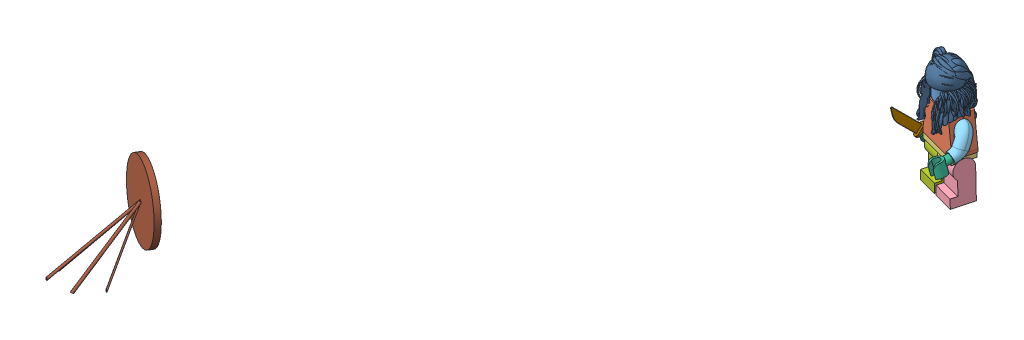
SolidWorks assembly Assemblage, configuration Default. Lengths in mm.
Overall size (131.52 71.94 248.3).
12 component instances, 11 part files, 29 mates.
Components (placement in the parent):
- hoofd-1: hoofd [Default] at (-2.0828 -36.2697 -1.4267) size (10 11.6 10)
- lichaam-1: lichaam [Default] at (-0.9943 -15.0822 -5.4791) x (0.96577 0 0.259401) z (0 -1 0) size (15.5 8 19)
- heup-1: heup [Default] at (-2.2734 -17.0822 -1.6809) x (0.96577 0 0.259401) z (-0.259401 0 0.96577) size (15 13 8)
- been-1: been [Default] at (-2.9578 -30.7822 2.7948) x (0.259401 0 -0.96577) z (0.96577 0 0.259401) size (8 14.7 7.5)
- arm-1: arm [Default] at (3.5968 -9.7563 4.5247) x (-0.026152 0.882476 -0.469631) z (0.303007 -0.440693 -0.844971) size (12.24 7.31 6.32)
- hand-1: hand [Default] at (5.5563 -16.2399 9.9413) x (0.245917 0.147876 -0.957944) z (0.931709 0.236466 0.275685) size (11.35 5.13 4.9)
- been 2-1: been 2 [Default] at (-3.9236 -30.7822 2.5354) x (0.259401 0 -0.96577) z (0.96577 0 0.259401) size (8 14.7 7.5)
- arm 2-1: arm 2 [Default] at (-9.3758 -11.9015 -2.7495) x (0.069651 0.936883 0.342635) z (0.296051 0.308582 -0.903953) size (12.24 7.31 6.32)
- hand-2: hand [Default] at (-11.3115 -19.7842 -4.6791) x (0.346001 0.785161 -0.513619) z (0.810219 0.025999 0.585551) size (11.35 5.13 4.9)
- zwaard-1: zwaard [Default] at (-11.2642 -19.8461 -4.7418) x (0.025074 0.721033 -0.692447) z (0.880649 0.311875 0.356639) size (4.65 17.55 3)
- haar goed 2-1: haar goed 2 [Default] at (-2.3434 5.7178 -0.4565) x (0.96577 0 0.259401) z (-0.259401 0 0.96577) size (16.74 21.71 15.98)
- bord-1: bord [Default] at (-98.3719 -6.3664 211.8563) x (0.483872 -0.373764 -0.791308) z (0.871266 0.120776 0.475719) size (24.24 40.74 26.3)
Mates (geometry in assembly coordinates):
- Concentric1: concentric aligned: cone of hoofd-1 through (-2.0828 -2.0822 -1.4267) axis (0 1 0); cone of lichaam-1 through (-2.0828 -2.0822 -1.4267) axis (0 1 0)
- Coincident2: coincident anti-aligned: plane of hoofd-1 through (1.4172 -2.0822 -1.4267) normal (0 -1 0); plane of lichaam-1 through (-8.6227 -2.0822 0.7555) normal (0 1 0)
- Coincident3: coincident anti-aligned: plane of lichaam-1 through (4.4152 -15.0822 4.2574) normal (0 -1 0); plane of heup-1 through (4.9699 -15.0822 0.2646) normal (0 1 0)
- Coincident4: coincident aligned: plane of lichaam-1 through (-10.5543 -15.0822 0.2367) normal (-0.96577 0 -0.259401); plane of heup-1 through (-9.5167 -17.0822 -3.6264) normal (-0.96577 0 -0.259401)
- Coincident5: coincident aligned: plane of lichaam-1 through (-3.0695 -15.0822 2.247) normal (-0.259401 0 0.96577); plane of heup-1 through (3.9323 -17.0822 4.1277) normal (-0.259401 0 0.96577)
- Concentric4: concentric aligned: cylinder of heup-1 through (1.1068 -19.5822 -0.773) axis (-0.96577 0 -0.259401) radius 1.2; cylinder of been-1 through (1.6863 -19.5822 -0.6174) axis (-0.96577 0 -0.259401) radius 1.2
- Coincident6: coincident anti-aligned: plane of heup-1 through (-1.5008 -17.0822 -1.4734) normal (0.96577 0 0.259401); plane of been-1 through (-1.5008 -19.5822 -1.4734) normal (-0.96577 0 -0.259401)
- Concentric5: concentric aligned: cylinder of lichaam-1 through (3.2709 -6.61 -0.1917) axis (0.952629 0.164399 0.255872) radius 2; cylinder of arm-1 through (3.0804 -6.6429 -0.2429) axis (0.952629 0.164399 0.255872) radius 2
- Coincident7: coincident anti-aligned: plane of lichaam-1 through (4.4152 -14.0822 4.2574) normal (0.952629 0.164399 0.255872); plane of arm-1 through (4.9848 -7.7764 -1.9149) normal (-0.952629 -0.164399 -0.255872)
- Concentric7: concentric aligned: cylinder of arm-1 through (6.7141 -11.0017 1.5354) axis (-0.195767 -0.312388 0.929564) radius 1.125; cylinder of hand-1 through (6.7141 -11.0017 1.5354) axis (-0.195767 -0.312388 0.929564) radius 1.1
- Coincident9: coincident anti-aligned: plane of arm-1 through (5.7353 -12.5637 6.1832) normal (-0.195767 -0.312388 0.929564); plane of hand-1 through (5.7353 -12.5637 6.1832) normal (0.195767 0.312388 -0.929564)
- Concentric8: concentric aligned: cylinder of heup-1 through (-5.6536 -19.5822 -2.5888) axis (0.96577 0 0.259401) radius 1.2; cylinder of been 2-1 through (-6.233 -19.5822 -2.7444) axis (0.96577 0 0.259401) radius 1.2
- Coincident10: coincident anti-aligned: plane of heup-1 through (-3.046 -17.0822 -1.8884) normal (-0.96577 0 -0.259401); plane of been 2-1 through (-3.046 -19.5822 -1.8884) normal (0.96577 0 0.259401)
- Concentric9: concentric aligned: cylinder of lichaam-1 through (-7.3348 -6.61 -3.0404) axis (-0.952629 0.164399 -0.255872) radius 2; cylinder of arm 2-1 through (-7.1443 -6.6429 -2.9892) axis (-0.952629 0.164399 -0.255872) radius 2
- Coincident11: coincident anti-aligned: plane of lichaam-1 through (-10.5543 -14.0822 0.2367) normal (-0.952629 0.164399 -0.255872); plane of arm 2-1 through (-7.5689 -5.9256 -5.6373) normal (0.952629 -0.164399 0.255872)
- Concentric10: concentric aligned: cylinder of arm 2-1 through (-10.0756 -10.1232 -6.8181) axis (-0.258591 -0.880677 0.396912) radius 1.125; cylinder of hand-2 through (-10.0756 -10.1232 -6.8181) axis (-0.258591 -0.880677 0.396912) radius 1.1
- Coincident12: coincident anti-aligned: plane of arm 2-1 through (-11.3686 -14.5266 -4.8335) normal (-0.258591 -0.880677 0.396912); plane of hand-2 through (-11.3686 -14.5266 -4.8335) normal (0.258591 0.880677 -0.396912)
- Parallel1: parallel: plane of heup-1; plane of hand-1
- Coincident19: coincident: plane of hand-1; plane of hand-2
- Parallel2: parallel: plane of hand-1; plane of hand-2
- Parallel4: parallel: plane of hand-1; plane of hand-2
- Concentric11: concentric aligned: cylinder of hoofd-1 through (-2.0828 9.5178 -1.4267) axis (0 1 0) radius 2.45; cylinder of haar goed 2-1 through (-2.0828 9.4178 -1.4267) axis (0 1 0) radius 2.45
- Distance2: distance = 18 mm aligned: plane of haar goed 2-1; plane of heup-1
- Coincident25: coincident aligned: plane of lichaam-1; plane of haar goed 2-1 through (-2.3434 5.7178 -0.4565) normal (0.96577 0 0.259401)
- Concentric18: concentric: cylinder of hand-2 through (-40.145 -2.9344 91.7306) axis (-0.420508 0.742003 0.522115) radius 1.5; circle of zwaard-1
- Coincident29: coincident: plane of hand-2; plane of zwaard-1
- Coincident30: coincident: plane of hand-2; plane of zwaard-1
- Coincident32: coincident: plane of lichaam-1; plane of arm 2-1
- Concentric25: concentric: cylinder of lichaam-1 through (-7.3348 -6.61 -3.0404) axis (-0.952629 0.164399 -0.255872) radius 2; cylinder of arm 2-1 through (-7.1443 -6.6429 -2.9892) axis (-0.952629 0.164399 -0.255872) radius 2
